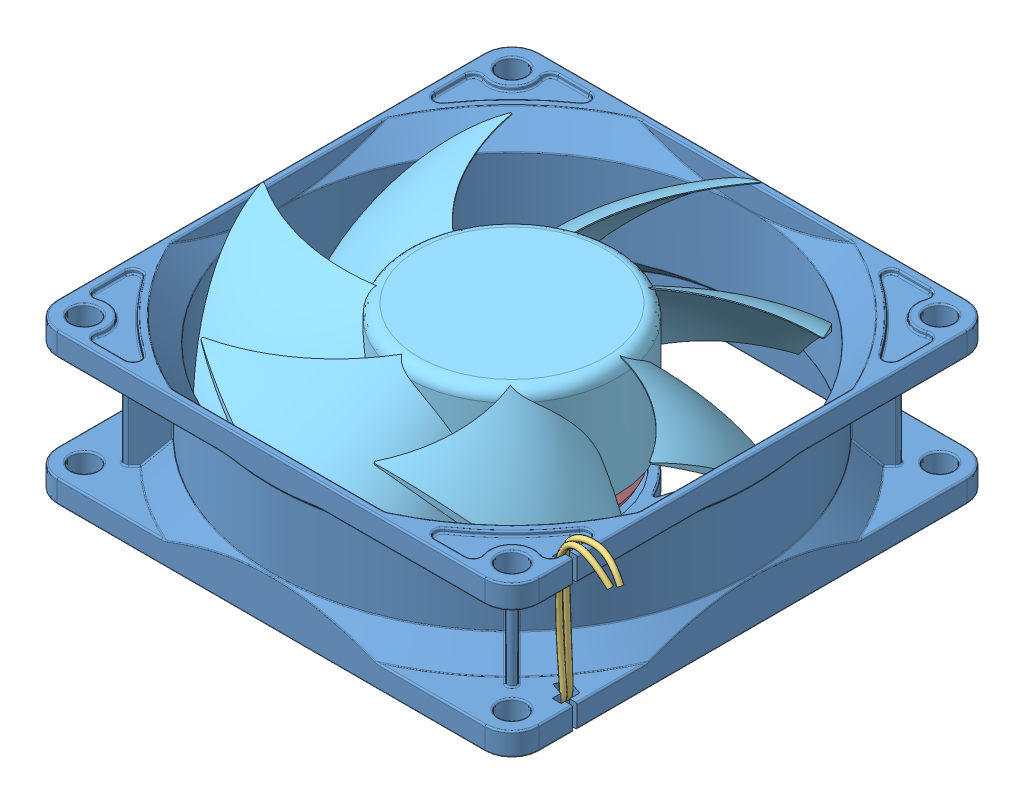
SolidWorks assembly Assem1, configuration Default. Lengths in mm.
Overall size (99.96 30.01 100.72).
8 component instances, 7 part files, 10 mates.
Components (placement in the parent):
- Part1-1: Part1 [Default] at origin size (85.02 27.66 85.07)
- Electrical Board^Assem1-1: Electrical Board^Assem1 [Default] at origin size (31 1.25 31) (virtual)
- Wires^Assem1-1: Wires^Assem1 [Default] at origin size (48.82 27.05 31.49) (virtual)
- Rotor-Short-1: Rotor-Short [Default] at (0 3.45 0) x (0.965926 0 0.258819) z (0 1 0) (suppressed, hidden)
- Part3-1: Part3 [Default] at (0 -7.75 0) x (-0.806154 0 0.591705) z (-0.591705 0 -0.806154) size (32 14 32)
- Part2-1: Part2 [Default] at (0 -4.55 0) x (0.333754 0 0.94266) z (-0.94266 0 0.333754) size (79.24 20.79 77.99)
- instrument ball bearing_68_am-1: instrument ball bearing_68_am [AFBMA 12.1.4.1 - 0020-5 - 10,SI,NC,10_68] at (0 -9 0) x (0 -1 0) z (0.007399 0 0.999973) size (1.5 5 5)
- instrument ball bearing_68_am-2: instrument ball bearing_68_am [AFBMA 12.1.4.1 - 0020-5 - 10,SI,NC,10_68] at (0 9.7 0) x (0 -1 0) z (0 0 1) size (1.5 5 5)
Mates (geometry in assembly coordinates):
- Concentric5: concentric anti-aligned: cylinder of Part1-1 through (0 -20.6495 0) axis (0 1 0) radius 2.5; cylinder of instrument ball bearing_68_am-1 through (0 11.6375 0) axis (0 -1 0) radius 2.5
- Coincident6: coincident anti-aligned: plane of Part1-1 through (0 -9.75 0) normal (0 1 0); plane of instrument ball bearing_68_am-1 through (1.08 -9.75 -0.008) normal (0 -1 0)
- Concentric6: concentric aligned: cylinder of Rotor-Short-1 through (0 22.45 0) axis (0 -1 0) radius 1; cylinder of instrument ball bearing_68_am-1 through (0 11.6375 0) axis (0 -1 0) radius 1
- Coincident7: coincident anti-aligned: plane of Rotor-Short-1 through (-1.4006 -8.25 -0.3753) normal (0 -1 0); plane of instrument ball bearing_68_am-1 through (1.45 -8.25 -0.0107) normal (0 1 0)
- Concentric7: concentric anti-aligned: cylinder of Part2-1 through (0 8.45 0) axis (0 1 0) radius 2.5; cylinder of instrument ball bearing_68_am-2 through (0 30.3375 0) axis (0 -1 0) radius 2.5
- Coincident8: coincident anti-aligned: plane of Part2-1 through (0 10.45 0) normal (0 -1 0); plane of instrument ball bearing_68_am-2 through (1.45 10.45 0) normal (0 1 0)
- Concentric9: concentric aligned: cylinder of Rotor-Short-1 through (0 22.45 0) axis (0 -1 0) radius 1; cylinder of Part3-1 through (0 6.25 0) axis (0 -1 0) radius 16
- Coincident9: coincident anti-aligned: plane of Electrical Board^Assem1-1 through (0 -7.75 0) normal (0 1 0); plane of Part3-1 through (0 -7.75 0) normal (0 -1 0)
- Concentric10: concentric anti-aligned: cylinder of Part3-1 through (0 6.25 0) axis (0 -1 0) radius 16; cylinder of Part2-1 through (0 -5.177 0) axis (0 1 0) radius 16
- Coincident11: coincident anti-aligned: plane of Rotor-Short-1 through (0 10.45 0) normal (0 1 0); plane of Part2-1 through (0 10.45 0) normal (0 -1 0)
